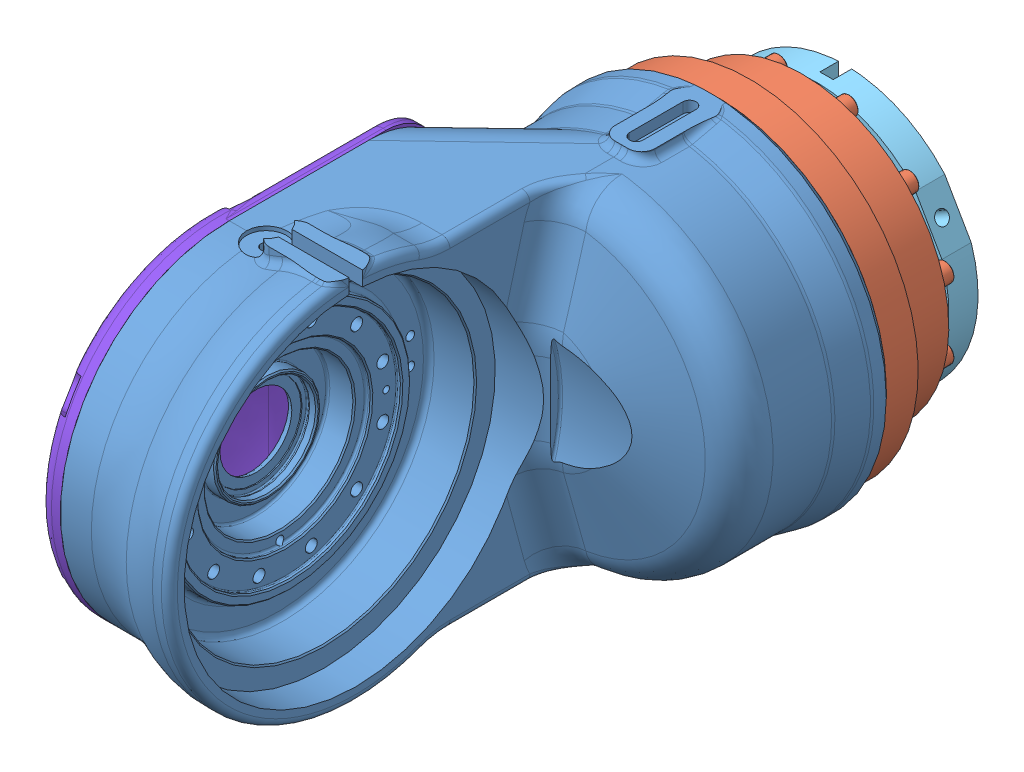
SolidWorks assembly ASM-B__ASM, configuration Valor predeterminado. Lengths in mm.
Overall size (179.61 179.61 250).
8 component instances, 8 part files, 0 mates.
Components (placement in the parent):
- WRIST_-1: WRIST_ [Valor predeterminado] x (-1 0 0) z (0 0 -1) size (132.53 151.99 202)
- AC25_-1: AC25_ [Valor predeterminado] at (0 0 -132) x (0.707107 -0.707107 0) z (-0.707107 -0.707107 0) size (127 90.45 127)
- 0411563_1_-1: 0411563_1_ [Valor predeterminado] at (0 0 -85.4) x (0 0 -1) z (-0.707107 -0.707107 0) size (90 55 51)
- 0411591_1_-1: 0411591_1_ [Valor predeterminado] at (0 0 -165.6) x (1 0 0) z (0 0 -1) size (55 55 5.4)
- FRANG_-1: FRANG_ [Valor predeterminado] at (0 0 -166) x (-1 0 0) z (0 0 -1) size (100 100 15.8)
- SPO_T_-1: SPO_T_ [Valor predeterminado] at (-42.5 -5 -45) x (0 0 -1) z (0 1 0) size (51.29 31.99 51.16)
- KU6BOLT_M4X5_SS_-1: KU6BOLT_M4X5_SS_ [Valor predeterminado] at (-45.4 26.8701 -26.8701) x (0 1 0) z (0 0 1) size (7 9 7)
- W-KABA_-1: W-KABA_ [Valor predeterminado] at (-51.5 0 0) x (0 1 0) z (0 0 1) size (131.95 41.18 147.12)
